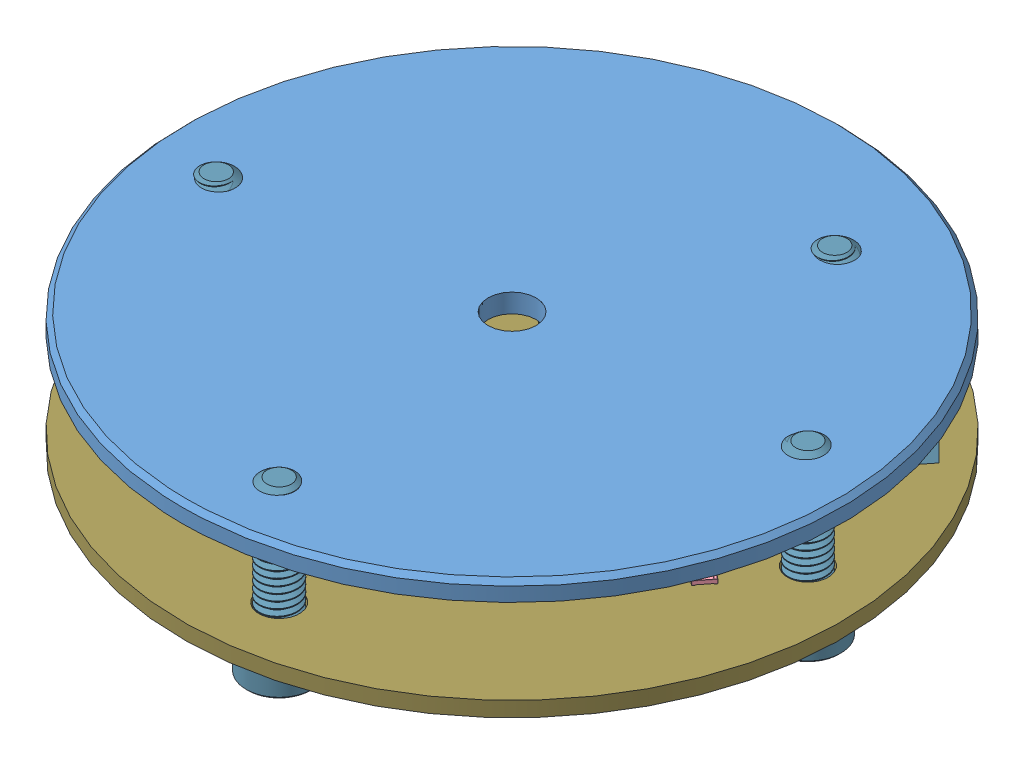
SolidWorks assembly PCB_retainer_Asm, configuration Default. Lengths in mm.
Overall size (98.34 18.34 98.34).
78 component instances, 14 part files, 19 mates.
Components (placement in the parent):
- Retaining plate-1: Retaining plate [Default] at origin size (70.03 2 70.03)
- BansheePCB-1: BansheePCB [Default] at (49.813 -10.6 179.2168) x (-0.785717 0 -0.618586) z (0 1 0) size (70.03 70.03 10.55)
  - PT0.step-1: PT0.step [Default] at origin size (70.03 70.03 10.55)
    - PinHeader_2x05_P1.27mm_Vertical.step-1: PinHeader_2x05_P1.27mm_Vertical.step [Default] at (148.25 -130.23 -0.05) x (1 0 0) z (0 0 -1) size (3.4 6.35 6.3)
      - SOLID.step-1: SOLID.step [Default] at origin size (3.4 6.35 6.3)
    - SOT-23.step-1: SOT-23.step [Default] at (138 -129 1.65) size (2.5 3 1.2)
      - SOLID-0.step-1: SOLID-0.step [Default] at origin size (2.5 3 1.2)
    - SOT-23.step-2: SOT-23.step [Default] at (138 -124 1.65) size (2.5 3 1.2)
      - SOLID-0.step-1: SOLID-0.step [Default] at origin size (2.5 3 1.2)
    - R_0805_2012Metric.step-1: R_0805_2012Metric.step [Default] at (177.975 -120 1.65) size (2 1.2 0.45)
      - SOLID-1.step-1: SOLID-1.step [Default] at origin size (2 1.2 0.45)
    - R_0805_2012Metric.step-2: R_0805_2012Metric.step [Default] at (144 -95.975 1.65) x (0 1 0) z (0 0 1) size (2 1.2 0.45)
      - SOLID-1.step-1: SOLID-1.step [Default] at origin size (2 1.2 0.45)
    - R_0805_2012Metric.step-3: R_0805_2012Metric.step [Default] at (146 -96.025 1.65) x (0 1 0) z (0 0 1) size (2 1.2 0.45)
      - SOLID-1.step-1: SOLID-1.step [Default] at origin size (2 1.2 0.45)
    - JST_PH_S2B-PH-K_1x02_P2.00mm_Horizontal.step-1: JST_PH_S2B-PH-K_1x02_P2.00mm_Horizontal.step [Default] at (146 -140 1.65) x (-1 0 0) z (0 0 1) size (5.9 7.6 8.25)
      - SOLID-2.step-1: SOLID-2.step [Default] at origin size (5.9 7.6 8.25)
    - C_0603_1608Metric.step-1: C_0603_1608Metric.step [Default] at (163.7875 -114 1.65) size (1.6 0.8 0.8)
      - SOLID-3.step-1: SOLID-3.step [Default] at origin size (1.6 0.8 0.8)
    - C_0603_1608Metric.step-2: C_0603_1608Metric.step [Default] at (157 -117.7875 1.65) x (0 -1 0) z (0 0 1) size (1.6 0.8 0.8)
      - SOLID-3.step-1: SOLID-3.step [Default] at origin size (1.6 0.8 0.8)
    - QFN-24-1EP_4x4mm_P0.5mm_EP2.7x2.6mm.step-1: QFN-24-1EP_4x4mm_P0.5mm_EP2.7x2.6mm.step [Default] at (176.05 -112.25 1.65) size (4 4 1.1)
      - SOLID-4.step-1: SOLID-4.step [Default] at origin size (4 4 1.1)
    - Bosch_LGA-8_2x2.5mm_P0.65mm_ClockwisePinNumbering.step-1: Bosch_LGA-8_2x2.5mm_P0.65mm_ClockwisePinNumbering.step [Default] at (150 -110 1.65) size (2.5 2 0.78)
      - SOLID-5.step-1: SOLID-5.step [Default] at origin size (2.5 2 0.78)
    - LQFP-48_7x7mm_P0.5mm.step-1: LQFP-48_7x7mm_P0.5mm.step [Default] at (169 -127 1.65) x (0.707107 -0.707107 0) z (0 0 1) size (9 9 1.5)
      - SOLID-6.step-1: SOLID-6.step [Default] at origin size (9 9 1.5)
    - R_0805_2012Metric.step-4: R_0805_2012Metric.step [Default] at (155 -95.975 1.65) x (0 1 0) z (0 0 1) size (2 1.2 0.45)
      - SOLID-1.step-1: SOLID-1.step [Default] at origin size (2 1.2 0.45)
    - R_0805_2012Metric.step-5: R_0805_2012Metric.step [Default] at (142.975 -121 1.65) size (2 1.2 0.45)
      - SOLID-1.step-1: SOLID-1.step [Default] at origin size (2 1.2 0.45)
    - R_0805_2012Metric.step-6: R_0805_2012Metric.step [Default] at (129 -122 1.65) x (0 1 0) z (0 0 1) size (2 1.2 0.45)
      - SOLID-1.step-1: SOLID-1.step [Default] at origin size (2 1.2 0.45)
    - R_0805_2012Metric.step-7: R_0805_2012Metric.step [Default] at (164 -116.975 1.65) x (0 -1 0) z (0 0 1) size (2 1.2 0.45)
      - SOLID-1.step-1: SOLID-1.step [Default] at origin size (2 1.2 0.45)
    - R_0805_2012Metric.step-8: R_0805_2012Metric.step [Default] at (143 -119 1.65) size (2 1.2 0.45)
      - SOLID-1.step-1: SOLID-1.step [Default] at origin size (2 1.2 0.45)
    - R_0805_2012Metric.step-9: R_0805_2012Metric.step [Default] at (131 -121.975 1.65) x (0 1 0) z (0 0 1) size (2 1.2 0.45)
      - SOLID-1.step-1: SOLID-1.step [Default] at origin size (2 1.2 0.45)
    - LED_0805_2012Metric.step-1: LED_0805_2012Metric.step [Default] at (149.025 -121 -0.05) x (-1 0 0) z (0 0 -1) size (2 1.25 1.1)
      - SOLID-7.step-1: SOLID-7.step [Default] at origin size (2 1.25 1.1)
    - LED_0805_2012Metric.step-2: LED_0805_2012Metric.step [Default] at (149.025 -119 -0.05) x (-1 0 0) z (0 0 -1) size (2 1.25 1.1)
      - SOLID-7.step-1: SOLID-7.step [Default] at origin size (2 1.25 1.1)
    - C_0805_2012Metric.step-1: C_0805_2012Metric.step [Default] at (177.975 -118 1.65) x (-1 0 0) z (0 0 1) size (2 1.25 1.25)
      - SOLID-8.step-1: SOLID-8.step [Default] at origin size (2 1.25 1.25)
    - C_0805_2012Metric.step-2: C_0805_2012Metric.step [Default] at (177 -106 1.65) x (0 -1 0) z (0 0 1) size (2 1.25 1.25)
      - SOLID-8.step-1: SOLID-8.step [Default] at origin size (2 1.25 1.25)
    - C_0805_2012Metric.step-3: C_0805_2012Metric.step [Default] at (181 -111.975 1.65) x (0 -1 0) z (0 0 1) size (2 1.25 1.25)
      - SOLID-8.step-1: SOLID-8.step [Default] at origin size (2 1.25 1.25)
    - C_0805_2012Metric.step-4: C_0805_2012Metric.step [Default] at (173.025 -116 1.65) x (-1 0 0) z (0 0 1) size (2 1.25 1.25)
      - SOLID-8.step-1: SOLID-8.step [Default] at origin size (2 1.25 1.25)
    - C_0805_2012Metric.step-5: C_0805_2012Metric.step [Default] at (139 -109.975 1.65) x (0 -1 0) z (0 0 1) size (2 1.25 1.25)
      - SOLID-8.step-1: SOLID-8.step [Default] at origin size (2 1.25 1.25)
    - C_0805_2012Metric.step-6: C_0805_2012Metric.step [Default] at (161.975 -81 1.65) size (2 1.25 1.25)
      - SOLID-8.step-1: SOLID-8.step [Default] at origin size (2 1.25 1.25)
    - C_0805_2012Metric.step-7: C_0805_2012Metric.step [Default] at (139 -114 1.65) x (0 -1 0) z (0 0 1) size (2 1.25 1.25)
      - SOLID-8.step-1: SOLID-8.step [Default] at origin size (2 1.25 1.25)
    - C_0805_2012Metric.step-8: C_0805_2012Metric.step [Default] at (161.025 -121 1.65) x (-1 0 0) z (0 0 1) size (2 1.25 1.25)
      - SOLID-8.step-1: SOLID-8.step [Default] at origin size (2 1.25 1.25)
    - C_0805_2012Metric.step-9: C_0805_2012Metric.step [Default] at (161 -123 1.65) x (-1 0 0) z (0 0 1) size (2 1.25 1.25)
      - SOLID-8.step-1: SOLID-8.step [Default] at origin size (2 1.25 1.25)
    - C_0805_2012Metric.step-10: C_0805_2012Metric.step [Default] at (171 -119.025 1.65) x (0 1 0) z (0 0 1) size (2 1.25 1.25)
      - SOLID-8.step-1: SOLID-8.step [Default] at origin size (2 1.25 1.25)
    - C_0805_2012Metric.step-11: C_0805_2012Metric.step [Default] at (176 -129.025 1.65) x (-0.707107 -0.707107 0) z (0 0 1) size (2 1.25 1.25)
      - SOLID-8.step-1: SOLID-8.step [Default] at origin size (2 1.25 1.25)
    - C_0805_2012Metric.step-12: C_0805_2012Metric.step [Default] at (168 -119.025 1.65) x (0 1 0) z (0 0 1) size (2 1.25 1.25)
      - SOLID-8.step-1: SOLID-8.step [Default] at origin size (2 1.25 1.25)
    - C_0805_2012Metric.step-13: C_0805_2012Metric.step [Default] at (169 -135.025 1.65) x (0 -1 0) z (0 0 1) size (2 1.25 1.25)
      - SOLID-8.step-1: SOLID-8.step [Default] at origin size (2 1.25 1.25)
    - COMPOUND.step-1: COMPOUND.step [Default] at origin size (70.03 70.03 1.6)
- 90965A150_TYPE 316 STAINLESS STEEL FLAT WASHER-1: 90965A150_TYPE 316 STAINLESS STEEL FLAT WASHER [90965A150] at (-28.0861 -11.5 3.3426) x (-0.85321 0 -0.521568) z (0 1 0) size (9 9 0.9)
- 91290A150_BLACK-OXIDE CLASS 12.9 SOCKET HEAD CAP SCREW-1: 91290A150_BLACK-OXIDE CLASS 12.9 SOCKET HEAD CAP SCREW [91290A150] at (-28.0861 2.5 3.3426) x (-0.837169 0 -0.546944) z (0 1 0) size (7 7 18.34)
- 90965A150_TYPE 316 STAINLESS STEEL FLAT WASHER-2: 90965A150_TYPE 316 STAINLESS STEEL FLAT WASHER [90965A150] at (3.3426 -10.6 28.0861) x (1 0 0) z (0 -1 0) size (9 9 0.9)
- 91290A150_BLACK-OXIDE CLASS 12.9 SOCKET HEAD CAP SCREW-2: 91290A150_BLACK-OXIDE CLASS 12.9 SOCKET HEAD CAP SCREW [91290A150] at (3.3426 2.5 28.0861) x (0.792794 0 0.60949) z (0 1 0) size (7 7 18.34)
- 90965A150_TYPE 316 STAINLESS STEEL FLAT WASHER-3: 90965A150_TYPE 316 STAINLESS STEEL FLAT WASHER [90965A150] at (28.0861 -11.5 -3.3426) x (1 0 0) z (0 1 0) size (9 9 0.9)
- 91290A150_BLACK-OXIDE CLASS 12.9 SOCKET HEAD CAP SCREW-3: 91290A150_BLACK-OXIDE CLASS 12.9 SOCKET HEAD CAP SCREW [91290A150] at (28.0861 2.5 -3.3426) x (0.998932 0 0.046194) z (0 1 0) size (7 7 18.34)
- 90965A150_TYPE 316 STAINLESS STEEL FLAT WASHER-4: 90965A150_TYPE 316 STAINLESS STEEL FLAT WASHER [90965A150] at (11.5361 -11.5 -22.7359) x (-0.837169 0 -0.546944) z (0 1 0) size (9 9 0.9)
- 91290A150_BLACK-OXIDE CLASS 12.9 SOCKET HEAD CAP SCREW-4: 91290A150_BLACK-OXIDE CLASS 12.9 SOCKET HEAD CAP SCREW [91290A150] at (11.5361 2.5 -22.7359) x (-0.974335 0 0.225102) z (0 1 0) size (7 7 18.34)
Mates (geometry in assembly coordinates):
- Concentric1: concentric aligned: circle of Retaining plate-1; circle of BansheePCB-1/PT0.step-1/COMPOUND.step-1
- Concentric2: concentric aligned: cylinder of Retaining plate-1; cylinder of BansheePCB-1/PT0.step-1/COMPOUND.step-1 through (28.0861 -11.4 -3.3426) axis (0 1 0) radius 2.15
- Distance1: distance = 9 mm anti-aligned: plane of BansheePCB-1/PT0.step-1/COMPOUND.step-1 through (0 -9 0) normal (0 1 0); plane of Retaining plate-1 through (0 0 0) normal (0 -1 0)
- Concentric3: concentric aligned: circle of BansheePCB-1/PT0.step-1/COMPOUND.step-1; circle of 91290A150_BLACK-OXIDE CLASS 12.9 SOCKET HEAD CAP SCREW-1
- Concentric4: concentric aligned: circle of BansheePCB-1/PT0.step-1/COMPOUND.step-1; circle of 90965A150_TYPE 316 STAINLESS STEEL FLAT WASHER-1
- Coincident3: coincident anti-aligned: plane of BansheePCB-1/PT0.step-1/COMPOUND.step-1 through (0 -10.6 0) normal (0 -1 0); plane of 90965A150_TYPE 316 STAINLESS STEEL FLAT WASHER-1 through (-28.0861 -10.6 3.3426) normal (0 1 0)
- Coincident5: coincident anti-aligned: plane of 90965A150_TYPE 316 STAINLESS STEEL FLAT WASHER-1 through (-28.0861 -11.5 3.3426) normal (0 -1 0); plane of 91290A150_BLACK-OXIDE CLASS 12.9 SOCKET HEAD CAP SCREW-1 through (-28.0861 -11.5 3.3426) normal (0 1 0)
- Concentric5: concentric anti-aligned: circle of BansheePCB-1/PT0.step-1/COMPOUND.step-1; circle of 90965A150_TYPE 316 STAINLESS STEEL FLAT WASHER-2
- Coincident6: coincident anti-aligned: plane of BansheePCB-1/PT0.step-1/COMPOUND.step-1 through (0 -10.6 0) normal (0 -1 0); plane of 90965A150_TYPE 316 STAINLESS STEEL FLAT WASHER-2 through (3.3426 -10.6 28.0861) normal (0 1 0)
- Concentric6: concentric anti-aligned: circle of 90965A150_TYPE 316 STAINLESS STEEL FLAT WASHER-2; cylinder of 91290A150_BLACK-OXIDE CLASS 12.9 SOCKET HEAD CAP SCREW-2 through (3.3426 -15.5 28.0861) axis (0 1 0) radius 3.5
- Coincident7: coincident anti-aligned: plane of 90965A150_TYPE 316 STAINLESS STEEL FLAT WASHER-2 through (3.3426 -11.5 28.0861) normal (0 -1 0); plane of 91290A150_BLACK-OXIDE CLASS 12.9 SOCKET HEAD CAP SCREW-2 through (3.3426 -11.5 28.0861) normal (0 1 0)
- Coincident8: coincident anti-aligned: plane of BansheePCB-1/PT0.step-1/COMPOUND.step-1 through (0 -10.6 0) normal (0 -1 0); plane of 90965A150_TYPE 316 STAINLESS STEEL FLAT WASHER-3 through (28.0861 -10.6 -3.3426) normal (0 1 0)
- Coincident9: coincident aligned: circle of BansheePCB-1/PT0.step-1/COMPOUND.step-1; circle of 90965A150_TYPE 316 STAINLESS STEEL FLAT WASHER-3
- Concentric7: concentric anti-aligned: cylinder of 90965A150_TYPE 316 STAINLESS STEEL FLAT WASHER-3 through (28.0861 -10.6 -3.3426) axis (0 -1 0) radius 4.5; cylinder of 91290A150_BLACK-OXIDE CLASS 12.9 SOCKET HEAD CAP SCREW-3 through (28.0861 -15.5 -3.3426) axis (0 1 0) radius 3.5
- Coincident10: coincident anti-aligned: plane of 90965A150_TYPE 316 STAINLESS STEEL FLAT WASHER-3 through (28.0861 -11.5 -3.3426) normal (0 -1 0); plane of 91290A150_BLACK-OXIDE CLASS 12.9 SOCKET HEAD CAP SCREW-3 through (28.0861 -11.5 -3.3426) normal (0 1 0)
- Concentric8: concentric aligned: circle of BansheePCB-1/PT0.step-1/COMPOUND.step-1; circle of 90965A150_TYPE 316 STAINLESS STEEL FLAT WASHER-4
- Coincident11: coincident anti-aligned: plane of BansheePCB-1/PT0.step-1/COMPOUND.step-1 through (0 -10.6 0) normal (0 -1 0); plane of 90965A150_TYPE 316 STAINLESS STEEL FLAT WASHER-4 through (11.5361 -10.6 -22.7359) normal (0 1 0)
- Concentric9: concentric aligned: circle of 90965A150_TYPE 316 STAINLESS STEEL FLAT WASHER-4; cylinder of 91290A150_BLACK-OXIDE CLASS 12.9 SOCKET HEAD CAP SCREW-4 through (11.5361 -15.5 -22.7359) axis (0 1 0) radius 3.5
- Coincident12: coincident anti-aligned: plane of 90965A150_TYPE 316 STAINLESS STEEL FLAT WASHER-4 through (11.5361 -11.5 -22.7359) normal (0 -1 0); plane of 91290A150_BLACK-OXIDE CLASS 12.9 SOCKET HEAD CAP SCREW-4 through (11.5361 -11.5 -22.7359) normal (0 1 0)
